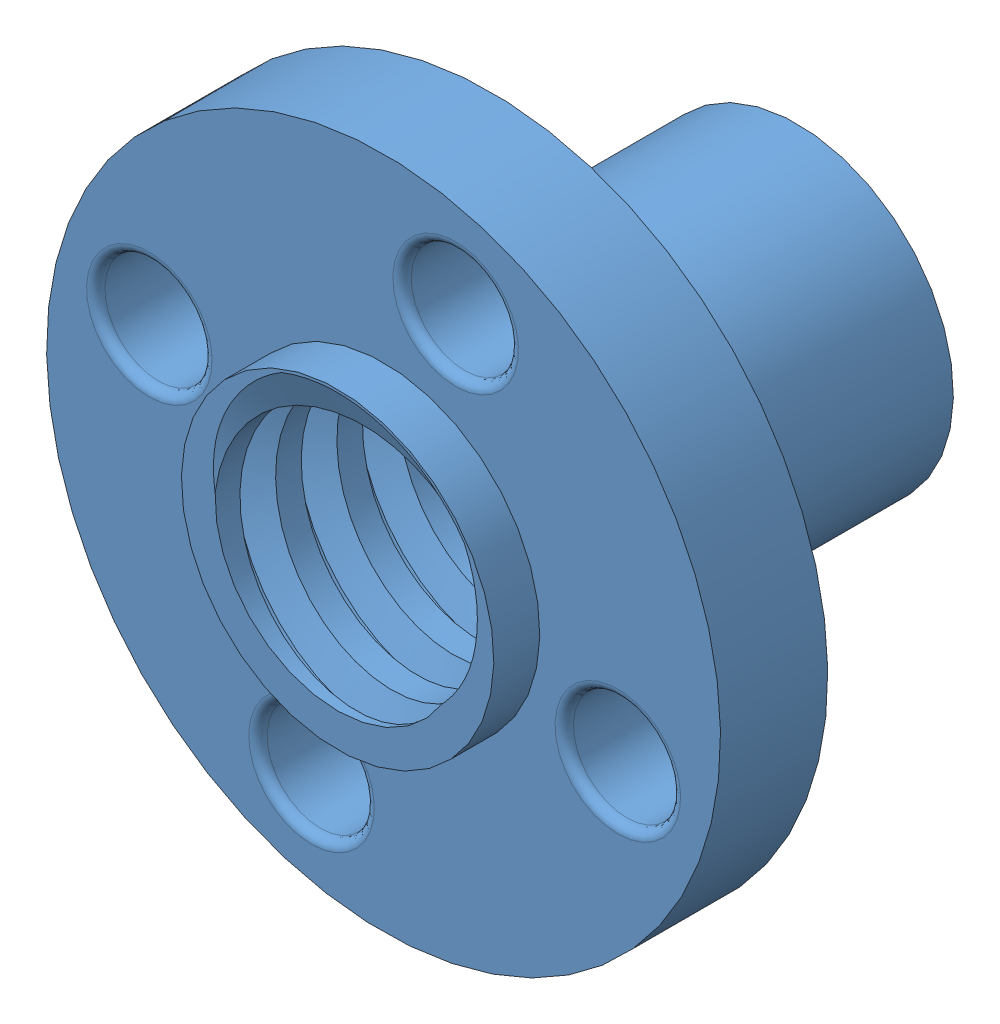
SolidWorks assembly Screw&Nut, configuration Default. Lengths in mm.
Overall size (47.12 49.11 25.52).
2 component instances, 2 part files, 3 mates.
Components (placement in the parent):
- LeadScrew Nut 8mm x 2mmPitch-1: LeadScrew Nut 8mm x 2mmPitch [Default] at (5.1353 112.62 348.5467) x (0.293962 0.955817 0) z (0 0 1) size (22 22 16.05)
- Lead Screw Nut_Housing(Z_Axis)-2: Lead Screw Nut_Housing(Z_Axis) [Default] at (5.1353 112.62 325.0467) x (0.293962 0.955817 0) z (0 0 1) size (40 37 20)
Mates (geometry in assembly coordinates):
- Concentric1: concentric: cylinder of assembly; cylinder of assembly; cylinder of LeadScrew Nut 8mm x 2mmPitch-1 through (5.1353 112.62 335.0467) axis (0 0 1) radius 5.1; cylinder of Lead Screw Nut_Housing(Z_Axis)-2 through (5.1353 112.62 345.0467) axis (0 0 -1) radius 5.25
- Concentric2: concentric: cylinder of assembly; cylinder of assembly; cylinder of LeadScrew Nut 8mm x 2mmPitch-1 through (2.7836 104.9735 345.0467) axis (0 0 1) radius 1.75; cylinder of Lead Screw Nut_Housing(Z_Axis)-2 through (2.7836 104.9735 345.0467) axis (0 0 -1) radius 2
- Coincident1: coincident: plane of assembly; plane of assembly; plane of LeadScrew Nut 8mm x 2mmPitch-1 through (5.1353 112.62 345.0467) normal (0 0 -1); plane of Lead Screw Nut_Housing(Z_Axis)-2 through (5.1353 112.62 345.0467) normal (0 0 1)
